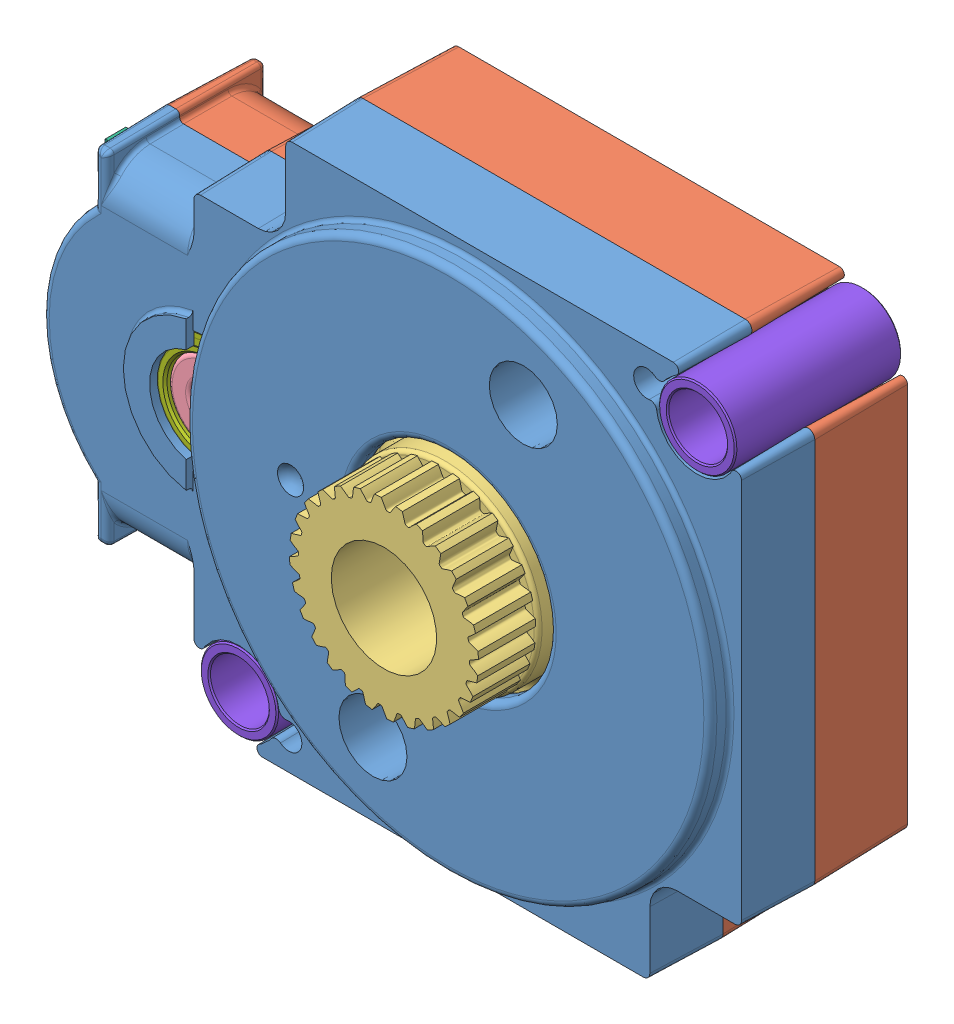
SolidWorks assembly 217-5046-STEP-20151201, configuration Default. Lengths in mm.
Overall size (58.21 43.13 22.65).
11 component instances, 10 part files, 0 mates.
Components (placement in the parent):
- 217-4783-001 Rev3-1: 217-4783-001 Rev3 [Default] at (0 0 2.75) size (53.55 42 11.11)
- 217-4783-002 Rev7_Sealed Config-1: 217-4783-002 Rev7_Sealed Config [Default] at (0 0 -7.2) x (0 1 0) z (0 0 1) size (42 51.56 9.32)
- 217-4783-005 Rev7_40t_spur_REF_14deg-1: 217-4783-005 Rev7_40t_spur_REF_14deg [Default] at (0 0 5.95) x (0.660339 0.750968 0) z (0 0 1) size (21.16 21.1 17.1)
- 217-4783-004 Rev2_40t_spur_REF_14deg-1: 217-4783-004 Rev2_40t_spur_REF_14deg [Default] at (-20.05 0 5.2) x (-0.718289 0.695745 0) z (0 0 1) size (21.07 21.07 4.88)
- 217-4783-008 Rev2-1: 217-4783-008 Rev2 [Default] at (-20.05 0 2.2) x (0.307149 -0.951661 0) z (0.951661 0.307149 0) size (5 4 5)
- PCBA Rev3-1: PCBA Rev3 [Default] at (-20.05 0 -2.1252) x (0 1 0) z (-1 0 0) size (15.93 10.15 24.58)
- 217-2788-001 Rev3_57155K375-1: 217-2788-001 Rev3_57155K375 [Default] at (-20.05 0 3.8125) x (-0.99574 0.092202 0) z (0 0 1) size (9.53 9.53 3.17)
- 217-4783-006 Rev3-1: 217-4783-006 Rev3 [Default] at (17.5 17.5 -0.85) x (-0.867641 0.497191 0) z (0 0 1) size (5.9 5.9 12.7)
- 217-4783-006 Rev3-2: 217-4783-006 Rev3 [Default] at (-17.5 -17.5 -0.85) x (0.825154 -0.564908 0) z (0 0 1) size (5.9 5.9 12.7)
- 217-4783-007 Rev1-1: 217-4783-007 Rev1 [Default] at (-16.45 0 -5.2) x (0 1 0) z (0 0 1) size (6 10.71 3.56)
- 217-4783-003 Rev4-1: 217-4783-003 Rev4 [Default] at (-20.05 0 -1.02) x (0 1 0) z (0 0 1) size (23.4 21.71 4.21)
